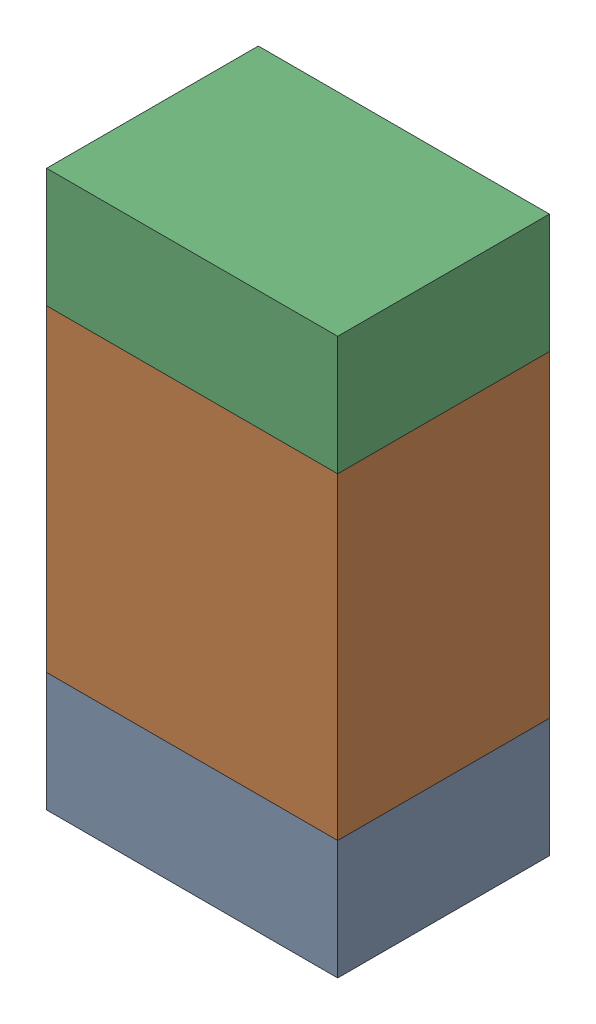
SolidWorks assembly R112_1PCB, configuration Default. Lengths in mm.
Overall size (0.55 1.05 0.4).
6 component instances, 2 part files, 0 mates.
Components (placement in the parent):
- 846483288-1: 846483288 [Default] at (115.6999 111.3876 0) size (0.55 0.22 0.4)
  - Extruded_12-1: Extruded_12 [Default] at origin size (0.55 0.22 0.4)
- 846483424-1: 846483424 [Default] at (115.6999 111.8001 0) size (0.55 0.6 0.4)
  - Extruded_13-1: Extruded_13 [Default] at origin size (0.55 0.6 0.4)
- 846483288-2: 846483288 [Default] at (115.6999 112.2126 0) size (0.55 0.22 0.4)
  - Extruded_12-1: Extruded_12 [Default] at origin size (0.55 0.22 0.4)
